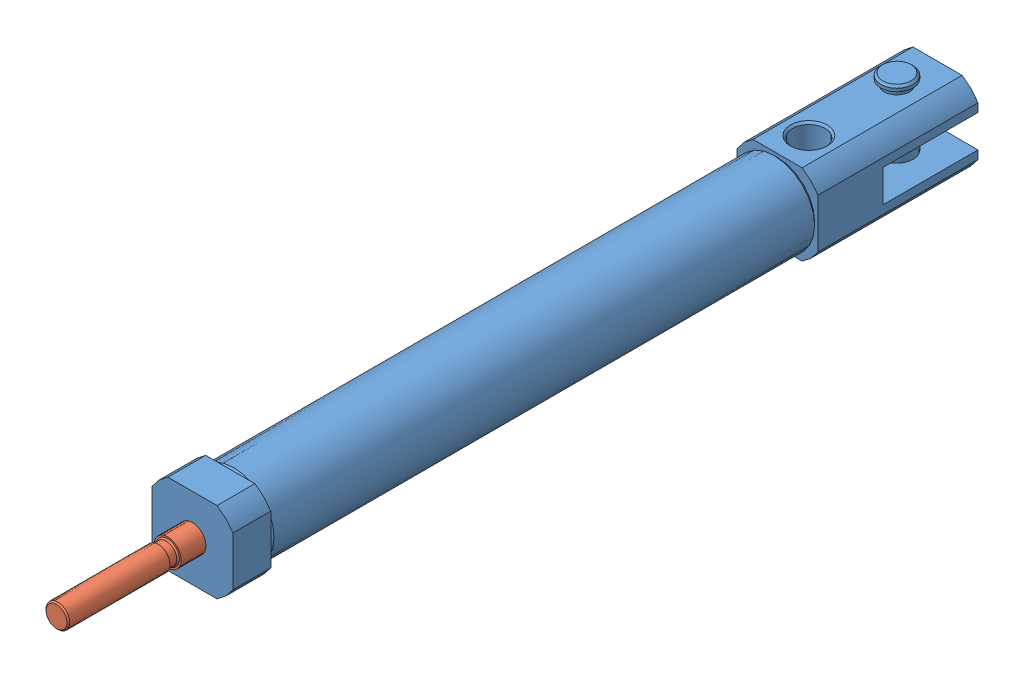
SolidWorks assembly Assem1, configuration Retracted. Lengths in mm.
Overall size (12.11 14.99 130.05).
2 component instances, 2 part files, 4 mates.
Components (placement in the parent):
- Body^Single Acting Cylinder-1: Body^Single Acting Cylinder [Default] at (38.7589 61.2952 91.9984) (virtual)
- Rod^Single Acting Cylinder-1: Rod^Single Acting Cylinder [Default] at (38.7589 61.2952 66.5984) x (-0.97058 0.240777 0) z (0 0 1) (virtual)
Mates (geometry in assembly coordinates):
- Concentric1: concentric aligned: cylinder of Copy of Body^Assem1-1 through (38.7589 61.2952 137.9724) axis (0 0 1) radius 2; cylinder of Rod^Assem1-1 through (38.7589 61.2952 69.0984) axis (0 0 1) radius 5
- LimitDistance1: limit distance = 0 mm anti-aligned: plane of Copy of Rod^Assem1-1 through (38.7589 61.2952 64.0984) normal (0 0 -1); plane of Body-1 through (38.7589 61.2952 64.0984) normal (0 0 1)
- Coincident1: coincident anti-aligned: plane of Copy of Body^Assem1-1 through (38.7589 61.2952 64.0984) normal (0 0 1); plane of Rod^Assem1-1 through (38.7589 61.2952 64.0984) normal (0 0 -1)
- Coincident2: coincident anti-aligned: plane of Copy of Body^Assem1-1 through (38.7589 61.2952 119.8984) normal (0 0 -1); plane of Rod^Assem1-1 through (38.7589 61.2952 119.8984) normal (0 0 1)
